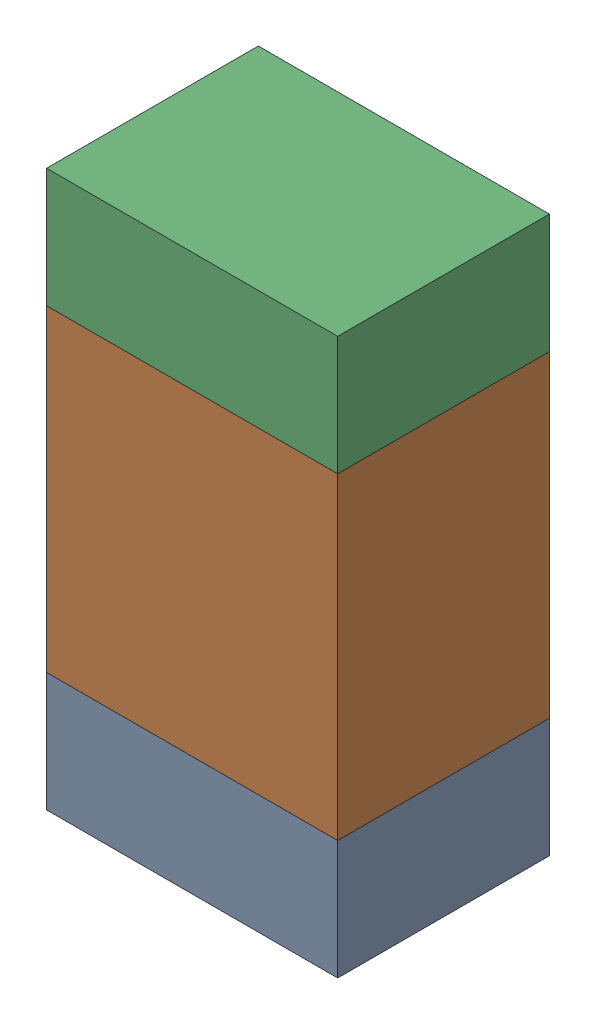
SolidWorks assembly R105_1PCB, configuration Default. Lengths in mm.
Overall size (0.55 1.05 0.4).
6 component instances, 2 part files, 0 mates.
Components (placement in the parent):
- 846483288-1: 846483288 [Default] at (117.5999 111.3876 0) size (0.55 0.22 0.4)
  - Extruded_12-1: Extruded_12 [Default] at origin size (0.55 0.22 0.4)
- 846483424-1: 846483424 [Default] at (117.5999 111.8001 0) size (0.55 0.6 0.4)
  - Extruded_13-1: Extruded_13 [Default] at origin size (0.55 0.6 0.4)
- 846483288-2: 846483288 [Default] at (117.5999 112.2126 0) size (0.55 0.22 0.4)
  - Extruded_12-1: Extruded_12 [Default] at origin size (0.55 0.22 0.4)
